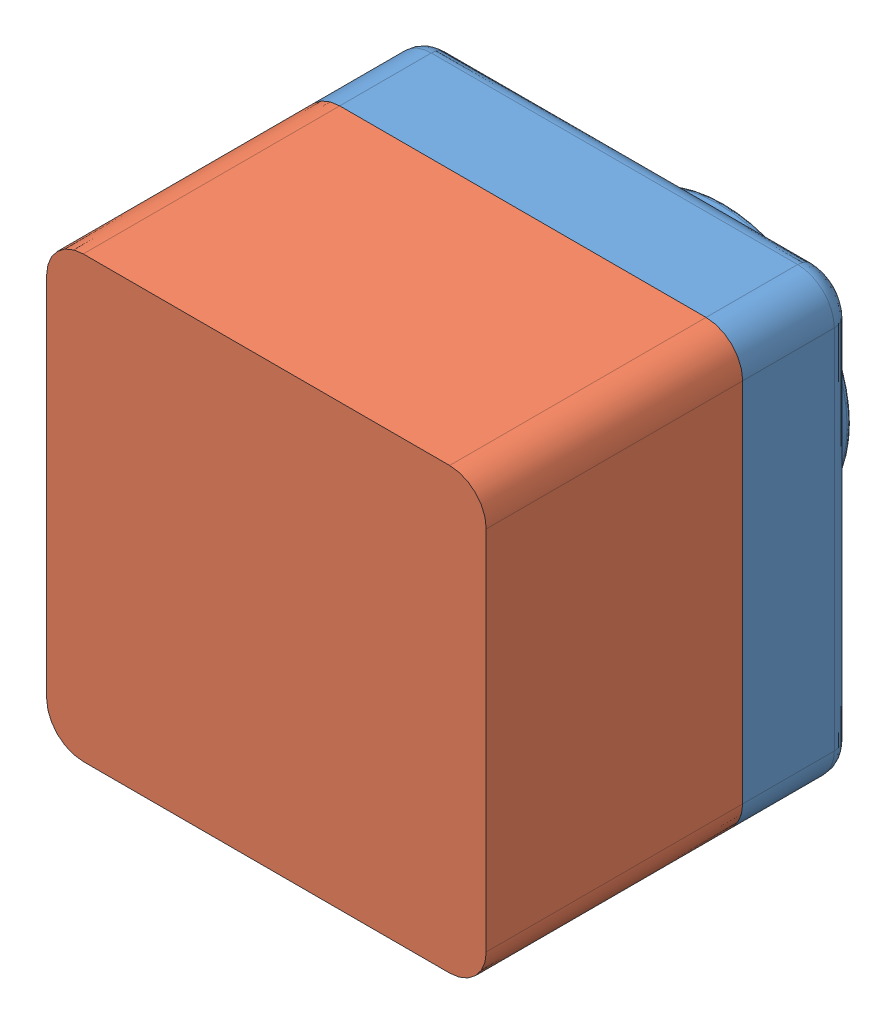
SolidWorks assembly full 1x1 lego, configuration Default. Lengths in mm.
Overall size (120 120 125).
2 component instances, 2 part files, 0 mates.
Components (placement in the parent):
- lego'-1: lego' [Default] at (94.6042 7.9309 102.9822) size (120 120 55)
- part 72 bottom lgeogeq-1: part 72 bottom lgeogeq [Default] at (-25.3958 7.9309 112.9822) size (120 120 90)
